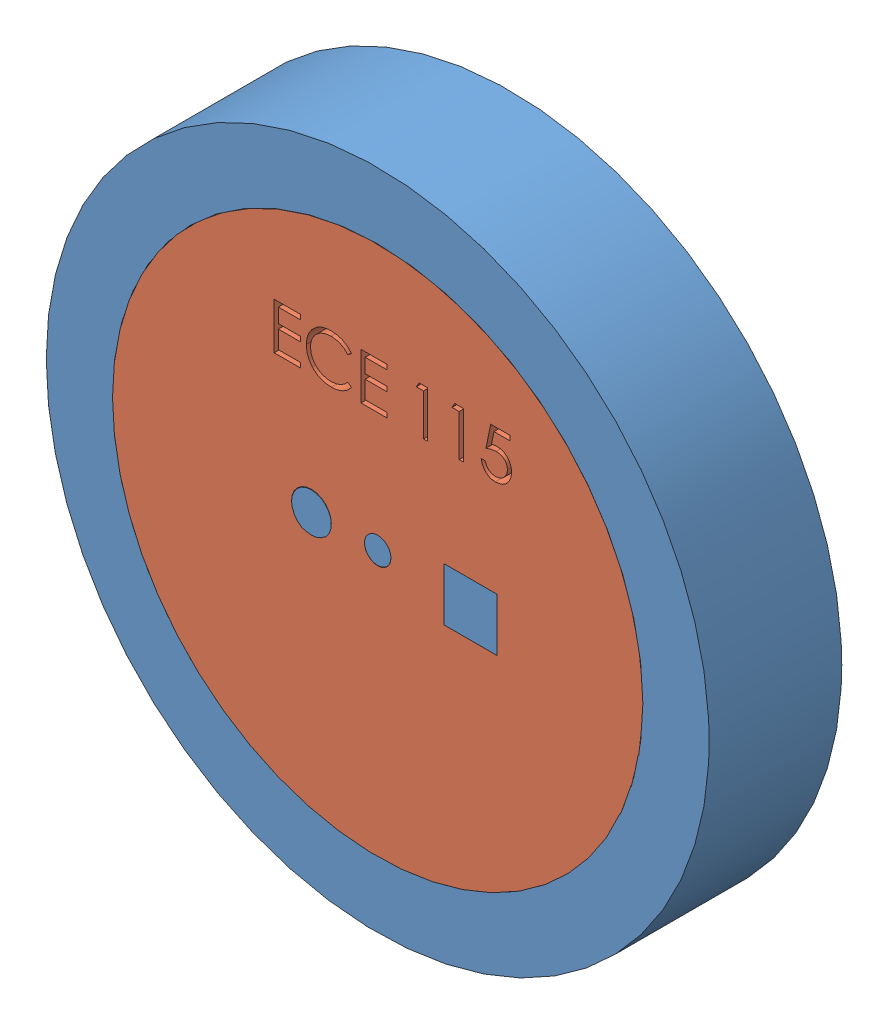
SolidWorks assembly Assem1, configuration Default. Lengths in mm.
Overall size (50 50 10).
2 component instances, 2 part files, 3 mates.
Components (placement in the parent):
- prelab part 1-2: prelab part 1 [Default] at (30.6002 -3.2399 36.5888) size (50 50 10)
- prelab part 2-3: prelab part 2 [Default] at (30.6002 -3.2613 41.5888) size (40 40 5)
Mates (geometry in assembly coordinates):
- Coincident17: coincident: plane of prelab part 1-2 through (30.6002 -3.2399 41.5888) normal (0 0 1); plane of prelab part 2-3 through (-4.9469 -3.2613 41.5888) normal (0 0 -1)
- Coincident18: coincident: plane of prelab part 1-2 through (35.6002 -1.6211 46.5888) normal (0 1 0); plane of prelab part 2-3 through (0.0531 -1.6211 41.5888) normal (0 -1 0)
- Coincident19: coincident anti-aligned: plane of prelab part 1-2 through (39.6002 -5.6211 46.5888) normal (1 0 0); plane of prelab part 2-3 through (39.6002 -1.6211 41.5888) normal (-1 0 0)
